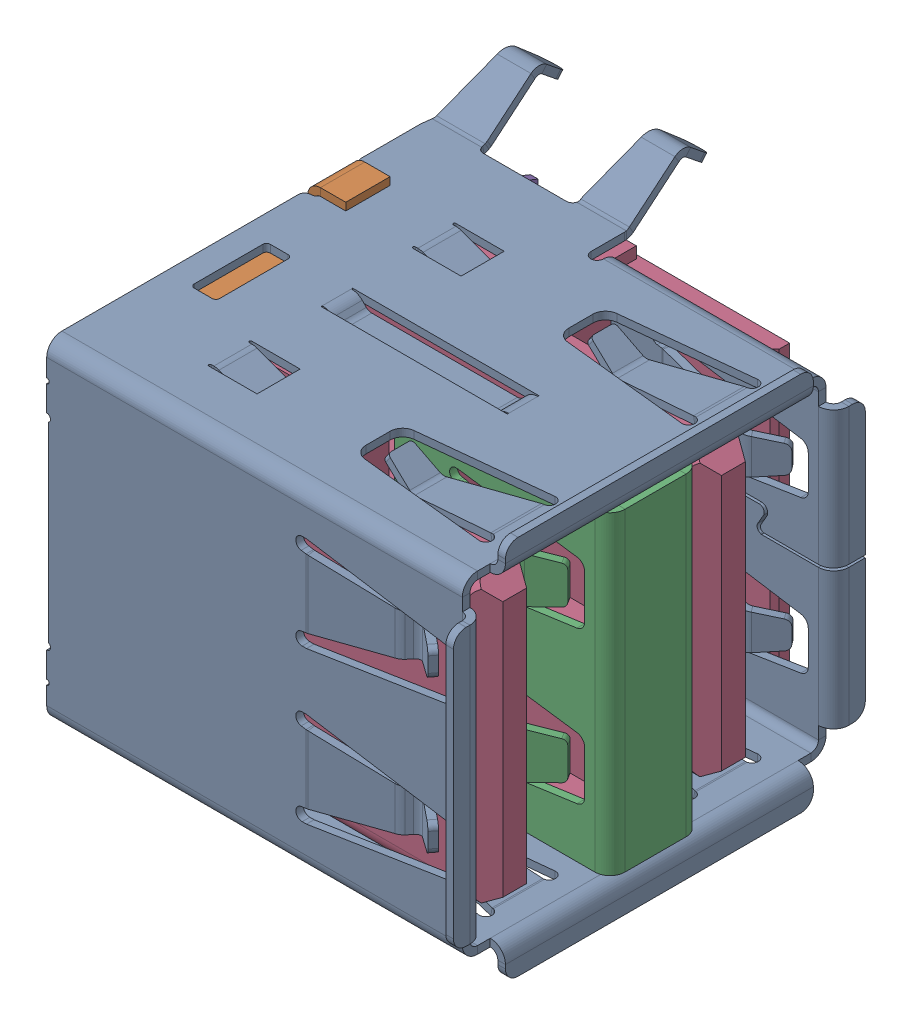
SolidWorks assembly USB-A-stack-1x2.stp, configuration Default. Lengths in mm.
Overall size (17 15.83 20.03).
15 component instances, 6 part files, 0 mates.
Components (placement in the parent):
- shell_1.stp-1: shell_1.stp [Default] at origin size (17 15.83 20.03)
  - outer.stp-1: outer.stp [Default] at origin size (17 15.83 20.03)
  - back_shell.stp-1: back_shell.stp [Default] at origin size (2.8 13.7 13.5)
  - mid_cover.stp-1: mid_cover.stp [Default] at origin size (8.5 12.4 5.09)
- Component4.stp-1: Component4.stp [Default] at origin size (16.25 12.4 15.02)
  - Component5.stp-1: Component5.stp [Default] at origin size (16.25 12.4 15.02)
- leads_1.stp-1: leads_1.stp [Default] at origin size (14.29 8.54 16.6)
  - top_lead.stp-1: top_lead.stp [Default] at origin size (14.29 1.54 16.6)
  - top_lead.stp-2: top_lead.stp [Default] at (0 -2.5 0) size (14.29 1.54 16.6)
  - top_lead.stp-3: top_lead.stp [Default] at (0 -7 0) size (14.29 1.54 16.6)
  - top_lead.stp-4: top_lead.stp [Default] at (0 -4.5 0) size (14.29 1.54 16.6)
  - bottom_lead.stp-1: bottom_lead.stp [Default] at origin size (11.67 1.54 7.97)
  - bottom_lead.stp-2: bottom_lead.stp [Default] at (0 -7 0) size (11.67 1.54 7.97)
  - bottom_lead.stp-3: bottom_lead.stp [Default] at (0 -2.5 0) size (11.67 1.54 7.97)
  - bottom_lead.stp-4: bottom_lead.stp [Default] at (0 -4.5 0) size (11.67 1.54 7.97)
